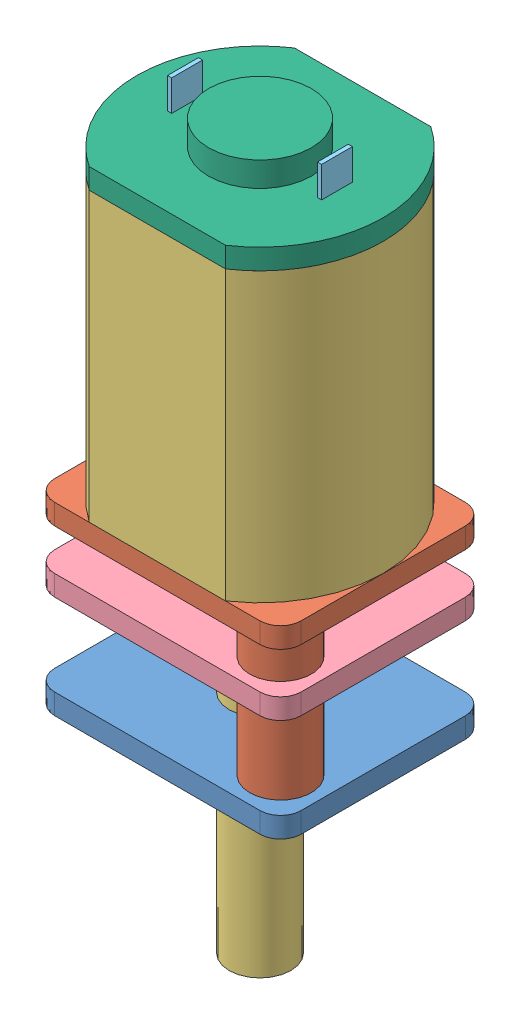
SolidWorks assembly User Library-N20, configuration Default. Lengths in mm.
Overall size (12 35.5 10).
6 component instances, 6 part files, 0 mates.
Components (placement in the parent):
- User Library-N20_Pad010-1: User Library-N20_Pad010 [Default] at (0 -23 0) x (1 0 0) z (0 -1 0) size (12 10 2)
- User Library-N20_Pad009-1: User Library-N20_Pad009 [Default] at (0 -15 0) x (1 0 0) z (0 -1 0) size (12 10 8.5)
- User Library-N20_Pad008-1: User Library-N20_Pad008 [Default] at (0 -1 0) x (1 0 0) z (0 -1 0) size (12 10 33)
- User Library-N20_Pad006-1: User Library-N20_Pad006 [Default] at (0 -18 0) x (1 0 0) z (0 -1 0) size (12 10 1)
- User Library-N20_Pad004-1: User Library-N20_Pad004 [Default] x (1 0 0) z (0 -1 0) size (7.5 1.5 1.5)
- User Library-N20_Pad003-1: User Library-N20_Pad003 [Default] x (1 0 0) z (0 -1 0) size (12 10 2.2)
